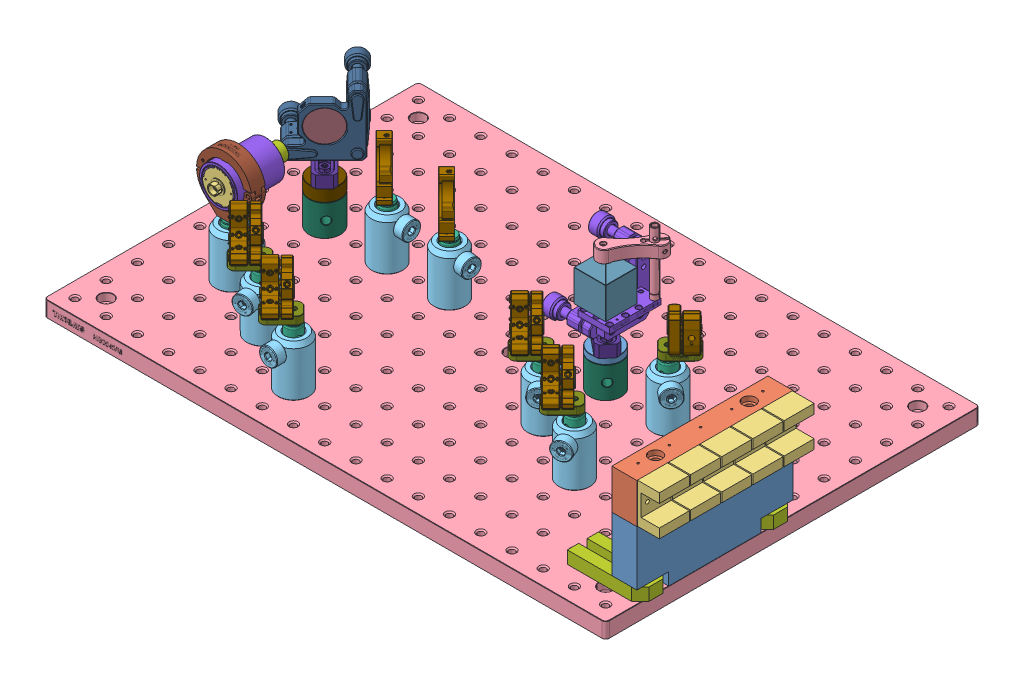
SolidWorks assembly Assem1, configuration Default. Lengths in mm.
Overall size (467.5 122.07 300).
67 component instances, 27 part files, 158 mates.
Components (placement in the parent):
- CC054-A - Base Mount-1: CC054-A - Base Mount [Default] at (68.9437 -53.2696 310.4338) x (0 0 1) z (-1 0 0) size (125 54 20)
- CC055-A - Diode Mount-1: CC055-A - Diode Mount [Default] at (58.9437 0.7304 247.9338) x (0 0 1) z (-1 0 0) size (125 32 20)
- CC056-A - Heatsink-1: CC056-A - Heatsink [Default] at (78.9437 16.7304 348.4338) x (0 -1 0) z (0 0 1) size (32 17.5 24)
- MB3045_M - 450x300M6-1: MB3045_M - 450x300M6 [Default] at (-146.0563 -65.9696 247.9338) size (450 12.7 300)
- PH40_M-P5 - Post Holder L40-1: PH40_M-P5 - Post Holder L40 [Default] at (-209.9469 -38.8243 365.1983) size (25 40.44 33)
- TR30_M-P5 - Optical Post L30-1: TR30_M-P5 - Optical Post L30 [Default] at (-33.5563 -34.349 310.4338) size (12.67 35.01 12.87)
- BA1S_M - Mounting Base-1: BA1S_M - Mounting Base [Default] at (51.1637 -48.2696 360.4338) size (58.42 10 24.99)
- KM100PM_M - Prism Mount L10-1: KM100PM_M - Prism Mount L10 [Default] at (-90.0598 -13.7458 200.6358) x (0 0 1) z (-1 0 0) size (52.45 52.45 53.15)
- KS05_M - Mirror Mount-1: KS05_M - Mirror Mount [Default] at (-35.115 17.2288 313.6155) x (-0.707107 0 -0.707107) z (0.707107 0 -0.707107) size (29.46 29.46 19.28)
- KS1 - Mirror Mount-1: KS1 - Mirror Mount [Default] at (-282.5729 -12.2533 247.4622) x (-0.707107 0 0.707107) z (-0.707107 0 -0.707107) size (52.45 52.45 42.47)
- PFM1_M - Flexure Mirror Mount-1: PFM1_M - Flexure Mirror Mount [Default] at (-127.9456 -10.3101 259.5463) x (-0.707107 0 0.707107) z (-0.707107 0 -0.707107) size (32.51 43.24 9.26) (hidden)
- SM1TC - Lens Tube Clamp-1: SM1TC - Lens Tube Clamp [Default] at (-308.5563 16.7304 310.4338) size (44.18 47.5 11.18)
- PF05-03-P01 - 05 Round Mirror-1: PF05-03-P01 - 05 Round Mirror [Default] at (-70.3657 -9.2592 301.8068) x (-0.608573 -0.509193 -0.608573) z (0.707107 0 -0.707107) size (12.7 12.7 6)
- PF10-03-P01 - 1 Round Mirror-1: PF10-03-P01 - 1 Round Mirror [Default] at (-300.01 11.2015 212.3567) x (0.707107 0 -0.707107) z (0.707107 0 0.707107) size (25.4 25.4 6)
- PBS251 - Polarizing Beamsplitter 420-680nm-1: PBS251 - Polarizing Beamsplitter 420-680nm [Default] at (-96.2563 5.3042 248.1338) size (25.4 25.4 25.4)
- RS25_M - Pillar Post L25-1: RS25_M - Pillar Post L25 [Default] at (-84.0904 -40.405 236.7511) x (0.655342 0 -0.755332) z (0.755332 0 0.655342) size (25 25 25.2)
- KCP05_M - Centering Plate-1: KCP05_M - Centering Plate [Default] at (-38.2619 1.9984 315.1394) x (0.707107 0 0.707107) z (0.707107 0 -0.707107) size (15.24 6.35 25.91)
- KMCP_M - Centering Plate-1: KMCP_M - Centering Plate [Default] at (-86.7824 -23.2708 232.8685) x (-0.632954 0 0.774189) z (0 1 0) size (15.24 34.29 9.53)
- RS10M - Post Spacer L10-1: RS10M - Post Spacer L10 [Default] at (-289.9454 -48.883 240.502) x (0.985186 0 -0.171489) z (0.171489 0 0.985186) size (25 10 25)
- RS5M - Post Spacer L05-1: RS5M - Post Spacer L05 [Default] at (-73.3037 -40.769 235.7337) x (0.8482 0 -0.529676) z (0.529676 0 0.8482) size (25 5 25)
- SM1A6 - SM1-SM05 Adapter-1: SM1A6 - SM1-SM05 Adapter [Default] at (-315.2083 22.6955 280.2399) x (0.870077 0.492915 0) z (0 0 1) size (26.29 26.29 3.81)
- SM1FC - Fiber Adapter-1: SM1FC - Fiber Adapter [Default] at (-308.5563 16.7304 321.2575) size (26.29 26.29 8.28)
- PM4_M - Clamp Arm M4-1: PM4_M - Clamp Arm M4 [Default] at (-67.8475 30.7042 211.9388) x (-0.60661 0 0.795) z (-0.795 0 -0.60661) size (43.81 55.88 12.78)
- A240TM-A - Rochester Aspheric Lens 350-700-1: A240TM-A - Rochester Aspheric Lens 350-700 [Default] at (66.5857 16.7304 360.4338) x (1 0 0) z (0 -0.655592 0.755115) size (6.86 12.24 12.24)
- AC127-019-A - Achromatic Doublet 350-700-1: AC127-019-A - Achromatic Doublet 350-700 [Default] at (-308.5563 16.7304 291.4495) x (-0.891118 -0.453772 0) z (0 0 -1) size (12.7 12.7 6)
- SM05V10 - Adjustable Lens Tube-1: SM05V10 - Adjustable Lens Tube [Default] at (-308.5563 16.7304 309.5608) x (0 0 1) z (0.988244 -0.152886 0) size (38.86 19.05 19.05)
- SM1M15 - Lens Tube-1: SM1M15 - Lens Tube [Default] at (-286.1396 25.3238 266.9462) x (-0.304458 0.952526 0) z (0 0 1) size (30.48 30.48 38.1)
- BA1S_M - Mounting Base-2: BA1S_M - Mounting Base [Default] at (51.1637 -48.2696 260.4338) size (58.42 10 24.99)
- CC056-A - Heatsink-2: CC056-A - Heatsink [Default] at (78.9437 16.7304 323.4338) x (0 -1 0) z (0 0 1) size (32 17.5 24)
- CC056-A - Heatsink-3: CC056-A - Heatsink [Default] at (78.9437 16.7304 298.4338) x (0 -1 0) z (0 0 1) size (32 17.5 24)
- CC056-A - Heatsink-4: CC056-A - Heatsink [Default] at (78.9437 16.7304 273.4338) x (0 -1 0) z (0 0 1) size (32 17.5 24)
- CC056-A - Heatsink-5: CC056-A - Heatsink [Default] at (78.9437 16.7304 248.4338) x (0 -1 0) z (0 0 1) size (32 17.5 24)
- PH40_M-P5 - Post Holder L40-2: PH40_M-P5 - Post Holder L40 [Default] at (-259.0241 -38.8243 340.375) x (0.982082 0 -0.188455) z (0.188455 0 0.982082) size (25 40.44 33)
- PH40_M-P5 - Post Holder L40-3: PH40_M-P5 - Post Holder L40 [Default] at (-32.9479 -38.8243 315.3596) x (0.918365 0 -0.395734) z (0.395734 0 0.918365) size (25 40.44 33)
- PH40_M-P5 - Post Holder L40-4: PH40_M-P5 - Post Holder L40 [Default] at (-81.8101 -38.8243 290.0798) x (0.8 0 -0.6) z (0.6 0 0.8) size (25 40.44 33)
- PH40_M-P5 - Post Holder L40-5: PH40_M-P5 - Post Holder L40 [Default] at (-30.7512 -38.8243 239.5284) x (0.63358 0 -0.773678) z (0.773678 0 0.63358) size (25 40.44 33)
- PH40_M-P5 - Post Holder L40-7: PH40_M-P5 - Post Holder L40 [Default] at (-154.3259 -38.8243 238.0295) x (0.263225 0 -0.964735) z (0.964735 0 0.263225) size (25 40.44 33) (hidden)
- PH40_M-P5 - Post Holder L40-8: PH40_M-P5 - Post Holder L40 [Default] at (-203.9934 -38.8243 237.3869) x (0.120178 0 -0.992752) z (0.992752 0 0.120178) size (25 40.44 33)
- PH40_M-P5 - Post Holder L40-9: PH40_M-P5 - Post Holder L40 [Default] at (-253.8362 -38.8243 236.9685) x (0.030377 0 -0.999538) z (0.999538 0 0.030377) size (25 40.44 33)
- PH40_M-P5 - Post Holder L40-10: PH40_M-P5 - Post Holder L40 [Default] at (-303.7918 -38.8243 311.8244) x (0 0 -1) z (1 0 0) size (25 40.44 33)
- TR30_M-P5 - Optical Post L30-2: TR30_M-P5 - Optical Post L30 [Default] at (-33.5563 -34.349 235.4338) x (0.982082 0 -0.188455) z (0.188455 0 0.982082) size (12.67 35.01 12.87)
- TR30_M-P5 - Optical Post L30-6: TR30_M-P5 - Optical Post L30 [Default] at (-83.5563 -34.349 285.4338) x (0.8 0 -0.6) z (0.6 0 0.8) size (12.67 35.01 12.87)
- TR30_M-P5 - Optical Post L30-8: TR30_M-P5 - Optical Post L30 [Default] at (-158.5563 -38.667 235.4338) x (0.63358 0 -0.773678) z (0.773678 0 0.63358) size (12.67 35.01 12.87) (hidden)
- TR30_M-P5 - Optical Post L30-10: TR30_M-P5 - Optical Post L30 [Default] at (-208.5563 -38.667 235.4338) x (0.443629 0 -0.896211) z (0.896211 0 0.443629) size (12.67 35.01 12.87)
- TR30_M-P5 - Optical Post L30-12: TR30_M-P5 - Optical Post L30 [Default] at (-208.5563 -34.349 360.4338) x (0.263225 0 -0.964735) z (0.964735 0 0.263225) size (12.67 35.01 12.87)
- TR30_M-P5 - Optical Post L30-14: TR30_M-P5 - Optical Post L30 [Default] at (-258.5563 -34.349 335.4338) x (0.120178 0 -0.992752) z (0.992752 0 0.120178) size (12.67 35.01 12.87)
- TR30_M-P5 - Optical Post L30-17: TR30_M-P5 - Optical Post L30 [Default] at (-258.5563 -38.667 235.4338) x (0.030377 0 -0.999538) z (0.999538 0 0.030377) size (12.67 35.01 12.87)
- TR30_M-P5 - Optical Post L30-19: TR30_M-P5 - Optical Post L30 [Default] at (-308.5563 -38.667 310.4338) x (0 0 -1) z (1 0 0) size (12.67 35.01 12.87)
- A240TM-A - Rochester Aspheric Lens 350-700-6: A240TM-A - Rochester Aspheric Lens 350-700 [Default] at (66.5857 16.7304 335.4338) x (1 0 0) z (0 -0.767025 0.641617) size (6.86 12.24 12.24)
- A240TM-A - Rochester Aspheric Lens 350-700-7: A240TM-A - Rochester Aspheric Lens 350-700 [Default] at (66.5857 16.7304 310.4338) x (1 0 0) z (0 -0.84248 0.538728) size (6.86 12.24 12.24)
- A240TM-A - Rochester Aspheric Lens 350-700-8: A240TM-A - Rochester Aspheric Lens 350-700 [Default] at (66.5857 16.7304 285.4338) x (1 0 0) z (0 -0.889028 0.457853) size (6.86 12.24 12.24)
- KCP05_M - Centering Plate-4: KCP05_M - Centering Plate [Default] at (-88.2619 1.9984 290.1394) x (0.707107 0 0.707107) z (0.707107 0 -0.707107) size (15.24 6.35 25.91)
- PF05-03-P01 - 05 Round Mirror-4: PF05-03-P01 - 05 Round Mirror [Default] at (-121.1332 -7.8569 276.0393) x (-0.62346 -0.471799 -0.62346) z (0.707107 0 -0.707107) size (12.7 12.7 6)
- KS05_M - Mirror Mount-4: KS05_M - Mirror Mount [Default] at (-85.115 17.2288 288.6155) x (-0.707107 0 -0.707107) z (0.707107 0 -0.707107) size (29.46 29.46 19.28)
- KCP05_M - Centering Plate-6: KCP05_M - Centering Plate [Default] at (-213.2619 1.9984 365.1394) x (0.707107 0 0.707107) z (0.707107 0 -0.707107) size (15.24 6.35 25.91)
- PF05-03-P01 - 05 Round Mirror-6: PF05-03-P01 - 05 Round Mirror [Default] at (-245.967 -8.1713 351.2055) x (-0.620263 -0.480155 -0.620263) z (0.707107 0 -0.707107) size (12.7 12.7 6)
- KS05_M - Mirror Mount-6: KS05_M - Mirror Mount [Default] at (-210.115 17.2288 363.6155) x (-0.707107 0 -0.707107) z (0.707107 0 -0.707107) size (29.46 29.46 19.28)
- KCP05_M - Centering Plate-8: KCP05_M - Centering Plate [Default] at (-263.2619 1.9984 340.1394) x (0.707107 0 0.707107) z (0.707107 0 -0.707107) size (15.24 6.35 25.91)
- PF05-03-P01 - 05 Round Mirror-8: PF05-03-P01 - 05 Round Mirror [Default] at (-295.0328 -9.8306 327.1397) x (-0.602026 -0.524528 -0.602026) z (0.707107 0 -0.707107) size (12.7 12.7 6)
- KS05_M - Mirror Mount-8: KS05_M - Mirror Mount [Default] at (-260.115 17.2288 338.6155) x (-0.707107 0 -0.707107) z (0.707107 0 -0.707107) size (29.46 29.46 19.28)
- KCP05_M - Centering Plate-10: KCP05_M - Centering Plate [Default] at (-28.8506 1.9984 230.7281) x (-0.707107 0 -0.707107) z (-0.707107 0 0.707107) size (15.24 6.35 25.91)
- PF05-03-P01 - 05 Round Mirror-10: PF05-03-P01 - 05 Round Mirror [Default] at (1.5654 -11.9598 242.373) x (0.574886 -0.582247 0.574886) z (-0.707107 0 0.707107) size (12.7 12.7 6)
- KS05_M - Mirror Mount-10: KS05_M - Mirror Mount [Default] at (-31.9976 17.2288 232.252) x (0.707107 0 0.707107) z (-0.707107 0 0.707107) size (29.46 29.46 19.28)
- PFM1_M - Flexure Mirror Mount-2: PFM1_M - Flexure Mirror Mount [Default] at (-232.6688 -10.3101 266.0445) x (-0.707107 0 -0.707107) z (0.707107 0 -0.707107) size (32.51 43.24 9.26)
- PFM1_M - Flexure Mirror Mount-4: PFM1_M - Flexure Mirror Mount [Default] at (-282.6688 -10.3101 266.0445) x (-0.707107 0 -0.707107) z (0.707107 0 -0.707107) size (32.51 43.24 9.26)
- RS25_M - Pillar Post L25-2: RS25_M - Pillar Post L25 [Default] at (-309.0904 -40.405 236.7511) x (0.655342 0 -0.755332) z (0.755332 0 0.655342) size (25 25 25.2)
- KMCP_M - Centering Plate-2: KMCP_M - Centering Plate [Default] at (-311.5101 -18.2696 232.5591) x (-0.707107 0 0.707107) z (0 1 0) size (15.24 34.29 9.53)
Mates (geometry in assembly coordinates):
- Concentric1: concentric: cylinder of CC054-A - Base Mount-1 through (68.9437 -43.2696 360.4338) axis (0 -1 0) radius 2.5; cylinder of BA1S_M - Mounting Base-1 through (68.9437 -53.2696 360.4338) axis (0 1 0) radius 3.3655
- Coincident1: coincident: plane of CC054-A - Base Mount-1 through (58.9437 -43.2696 347.4338) normal (0 -1 0); plane of BA1S_M - Mounting Base-1 through (2.8683 -43.2696 360.4338) normal (0 1 0)
- Parallel1: parallel: plane of CC054-A - Base Mount-1 through (58.9437 -43.2696 372.9338) normal (0 0 1); plane of BA1S_M - Mounting Base-1 through (2.8683 -53.2696 372.9306) normal (0 0 1)
- Concentric2: concentric: cylinder of CC054-A - Base Mount-1 through (68.9437 -43.2696 260.4338) axis (0 -1 0) radius 2.5; cylinder of BA1S_M - Mounting Base-2 through (68.9437 -53.2696 260.4338) axis (0 1 0) radius 3.3655
- Coincident2: coincident: plane of CC054-A - Base Mount-1 through (58.9437 -43.2696 247.9338) normal (0 -1 0); plane of BA1S_M - Mounting Base-2 through (2.8683 -43.2696 260.4338) normal (0 1 0)
- Parallel2: parallel: plane of CC054-A - Base Mount-1 through (58.9437 0.7304 247.9338) normal (0 0 -1); plane of BA1S_M - Mounting Base-2 through (2.8683 -53.2696 247.937) normal (0 0 -1)
- Coincident3: coincident: plane of MB3045_M - 450x300M6-1 through (-368.0563 -53.2696 394.9338) normal (0 1 0); plane of BA1S_M - Mounting Base-1 through (2.8683 -53.2696 360.4338) normal (0 -1 0)
- Coincident4: coincident: plane of CC054-A - Base Mount-1 through (78.9437 -53.2696 310.4338) normal (1 0 0); plane of MB3045_M - 450x300M6-1 through (78.9437 -53.2696 394.9338) normal (1 0 0)
- Concentric3: concentric: cylinder of CC054-A - Base Mount-1 through (68.9437 0.7304 347.9338) axis (0 1 0) radius 2.5; cylinder of CC055-A - Diode Mount-1 through (68.9437 32.7304 347.9338) axis (0 1 0) radius 5.25
- Concentric4: concentric: cylinder of CC054-A - Base Mount-1 through (68.9437 0.7304 272.9338) axis (0 1 0) radius 2.5; cylinder of CC055-A - Diode Mount-1 through (68.9437 32.7304 272.9338) axis (0 1 0) radius 5.25
- Coincident5: coincident: plane of CC054-A - Base Mount-1 through (58.9437 0.7304 372.9338) normal (0 1 0); plane of CC055-A - Diode Mount-1 through (58.9437 0.7304 247.9338) normal (0 -1 0)
- Concentric5: concentric: cylinder of CC055-A - Diode Mount-1 through (78.9437 16.7304 367.4338) axis (1 0 0) radius 1.25; cylinder of CC056-A - Heatsink-1 through (78.9427 16.7304 367.4338) axis (1 0 0) radius 1.5
- Concentric6: concentric: cylinder of CC055-A - Diode Mount-1 through (78.9437 16.7304 353.4338) axis (1 0 0) radius 1.25; cylinder of CC056-A - Heatsink-1 through (78.9427 16.7304 353.4338) axis (1 0 0) radius 1.5
- Coincident6: coincident: plane of CC055-A - Diode Mount-1 through (78.9437 32.7304 247.9338) normal (1 0 0); plane of CC056-A - Heatsink-1 through (78.9437 32.7304 372.4338) normal (-1 0 0)
- Coincident7: coincident: plane of CC055-A - Diode Mount-1 through (78.9437 32.7304 247.9338) normal (1 0 0); plane of CC056-A - Heatsink-2 through (78.9437 32.7304 347.4338) normal (-1 0 0)
- Concentric7: concentric: cylinder of CC055-A - Diode Mount-1 through (78.9437 16.7304 342.4338) axis (1 0 0) radius 1.25; cylinder of CC056-A - Heatsink-2 through (78.9427 16.7304 342.4338) axis (1 0 0) radius 1.5
- Concentric8: concentric: cylinder of CC055-A - Diode Mount-1 through (78.9437 16.7304 328.4338) axis (1 0 0) radius 1.25; cylinder of CC056-A - Heatsink-2 through (78.9427 16.7304 328.4338) axis (1 0 0) radius 1.5
- Coincident8: coincident: plane of CC055-A - Diode Mount-1 through (78.9437 32.7304 247.9338) normal (1 0 0); plane of CC056-A - Heatsink-3 through (78.9437 32.7304 322.4338) normal (-1 0 0)
- Concentric9: concentric: cylinder of CC055-A - Diode Mount-1 through (78.9437 16.7304 317.4338) axis (1 0 0) radius 1.25; cylinder of CC056-A - Heatsink-3 through (78.9427 16.7304 317.4338) axis (1 0 0) radius 1.5
- Concentric10: concentric: cylinder of CC055-A - Diode Mount-1 through (78.9437 16.7304 303.4338) axis (1 0 0) radius 1.25; cylinder of CC056-A - Heatsink-3 through (78.9427 16.7304 303.4338) axis (1 0 0) radius 1.5
- Coincident9: coincident: plane of CC055-A - Diode Mount-1 through (78.9437 32.7304 247.9338) normal (1 0 0); plane of CC056-A - Heatsink-4 through (78.9437 32.7304 297.4338) normal (-1 0 0)
- Concentric11: concentric: cylinder of CC055-A - Diode Mount-1 through (78.9437 16.7304 292.4338) axis (1 0 0) radius 1.25; cylinder of CC056-A - Heatsink-4 through (78.9427 16.7304 292.4338) axis (1 0 0) radius 1.5
- Concentric12: concentric: cylinder of CC055-A - Diode Mount-1 through (78.9437 16.7304 278.4338) axis (1 0 0) radius 1.25; cylinder of CC056-A - Heatsink-4 through (78.9427 16.7304 278.4338) axis (1 0 0) radius 1.5
- Coincident10: coincident: plane of CC055-A - Diode Mount-1 through (78.9437 32.7304 247.9338) normal (1 0 0); plane of CC056-A - Heatsink-5 through (78.9437 32.7304 272.4338) normal (-1 0 0)
- Concentric13: concentric: cylinder of CC055-A - Diode Mount-1 through (78.9437 16.7304 267.4338) axis (1 0 0) radius 1.25; cylinder of CC056-A - Heatsink-5 through (78.9427 16.7304 267.4338) axis (1 0 0) radius 1.5
- Concentric14: concentric: cylinder of CC055-A - Diode Mount-1 through (78.9437 16.7304 253.4338) axis (1 0 0) radius 1.25; cylinder of CC056-A - Heatsink-5 through (78.9427 16.7304 253.4338) axis (1 0 0) radius 1.5
- Width2: width: plane of BA1S_M - Mounting Base-1 through (2.8683 -53.2696 357.0683) normal (0 0 1); plane of BA1S_M - Mounting Base-1 through (2.8683 -53.2696 363.7993) normal (0 0 -1); cylinder of MB3045_M - 450x300M6-1 through (41.4437 -53.2696 360.4338) axis (0 1 0) radius 2.5
- Coincident12: coincident: plane of MB3045_M - 450x300M6-1 through (-368.0563 -53.2696 394.9338) normal (0 1 0); plane of PH40_M-P5 - Post Holder L40-1 through (-236.1977 -53.2696 360.4338) normal (0 -1 0)
- Concentric15: concentric: cylinder of MB3045_M - 450x300M6-1 through (-208.5563 -53.2696 360.4338) axis (0 1 0) radius 2.5; cylinder of PH40_M-P5 - Post Holder L40-1 through (-208.5563 -52.3806 360.4338) axis (0 -1 0) radius 2.5
- Coincident13: coincident: plane of MB3045_M - 450x300M6-1 through (-368.0563 -53.2696 394.9338) normal (0 1 0); plane of PH40_M-P5 - Post Holder L40-2 through (-285.7024 -53.2696 340.6429) normal (0 -1 0)
- Concentric16: concentric: cylinder of MB3045_M - 450x300M6-1 through (-258.5563 -53.2696 335.4338) axis (0 1 0) radius 2.5; cylinder of PH40_M-P5 - Post Holder L40-2 through (-258.5563 -52.3806 335.4338) axis (0 -1 0) radius 2.5
- Coincident14: coincident: plane of MB3045_M - 450x300M6-1 through (-368.0563 -53.2696 394.9338) normal (0 1 0); plane of PH40_M-P5 - Post Holder L40-3 through (-58.9412 -53.2696 321.3724) normal (0 -1 0)
- Concentric17: concentric: cylinder of MB3045_M - 450x300M6-1 through (-33.5563 -53.2696 310.4338) axis (0 1 0) radius 2.5; cylinder of PH40_M-P5 - Post Holder L40-3 through (-33.5563 -52.3806 310.4338) axis (0 -1 0) radius 2.5
- Coincident15: coincident: plane of MB3045_M - 450x300M6-1 through (-368.0563 -53.2696 394.9338) normal (0 1 0); plane of PH40_M-P5 - Post Holder L40-4 through (-105.6694 -53.2696 302.0186) normal (0 -1 0)
- Concentric18: concentric: cylinder of MB3045_M - 450x300M6-1 through (-83.5563 -53.2696 285.4338) axis (0 1 0) radius 2.5; cylinder of PH40_M-P5 - Post Holder L40-4 through (-83.5563 -52.3806 285.4338) axis (0 -1 0) radius 2.5
- Coincident16: coincident: plane of MB3045_M - 450x300M6-1 through (-368.0563 -53.2696 394.9338) normal (0 1 0); plane of PH40_M-P5 - Post Holder L40-5 through (-51.0693 -53.2696 256.8193) normal (0 -1 0)
- Concentric19: concentric: cylinder of MB3045_M - 450x300M6-1 through (-33.5563 -53.2696 235.4338) axis (0 1 0) radius 2.5; cylinder of PH40_M-P5 - Post Holder L40-5 through (-33.5563 -52.3806 235.4338) axis (0 -1 0) radius 2.5
- Coincident18: coincident: plane of MB3045_M - 450x300M6-1 through (-368.0563 -53.2696 394.9338) normal (0 1 0); plane of PH40_M-P5 - Post Holder L40-7 through (-165.8322 -53.2696 262.1004) normal (0 -1 0)
- Concentric21: concentric: cylinder of MB3045_M - 450x300M6-1 through (-158.5563 -53.2696 235.4338) axis (0 1 0) radius 2.5; cylinder of PH40_M-P5 - Post Holder L40-7 through (-158.5563 -52.3806 235.4338) axis (0 -1 0) radius 2.5
- Coincident19: coincident: plane of MB3045_M - 450x300M6-1 through (-368.0563 -53.2696 394.9338) normal (0 1 0); plane of PH40_M-P5 - Post Holder L40-8 through (-211.8782 -53.2696 262.8748) normal (0 -1 0)
- Concentric22: concentric: cylinder of MB3045_M - 450x300M6-1 through (-208.5563 -53.2696 235.4338) axis (0 1 0) radius 2.5; cylinder of PH40_M-P5 - Post Holder L40-8 through (-208.5563 -52.3806 235.4338) axis (0 -1 0) radius 2.5
- Coincident20: coincident: plane of MB3045_M - 450x300M6-1 through (-368.0563 -53.2696 394.9338) normal (0 1 0); plane of PH40_M-P5 - Post Holder L40-9 through (-259.3959 -53.2696 263.0624) normal (0 -1 0)
- Concentric23: concentric: cylinder of MB3045_M - 450x300M6-1 through (-258.5563 -53.2696 235.4338) axis (0 1 0) radius 2.5; cylinder of PH40_M-P5 - Post Holder L40-9 through (-258.5563 -52.3806 235.4338) axis (0 -1 0) radius 2.5
- Coincident21: coincident: plane of MB3045_M - 450x300M6-1 through (-368.0563 -53.2696 394.9338) normal (0 1 0); plane of PH40_M-P5 - Post Holder L40-10 through (-308.5563 -53.2696 338.0752) normal (0 -1 0)
- Concentric24: concentric: cylinder of MB3045_M - 450x300M6-1 through (-308.5563 -53.2696 310.4338) axis (0 1 0) radius 2.5; cylinder of PH40_M-P5 - Post Holder L40-10 through (-308.5563 -52.3806 310.4338) axis (0 -1 0) radius 2.5
- Concentric25: concentric: cylinder of TR30_M-P5 - Optical Post L30-1 through (-33.5563 -4.3516 310.4338) axis (0 1 0) radius 6.3373; cylinder of PH40_M-P5 - Post Holder L40-3 through (-33.5563 -13.2696 310.4338) axis (0 -1 0) radius 6.3881
- Concentric26: concentric: cylinder of PH40_M-P5 - Post Holder L40-5 through (-33.5563 -13.2696 235.4338) axis (0 -1 0) radius 6.3881; cylinder of TR30_M-P5 - Optical Post L30-2 through (-33.5563 -4.3516 235.4338) axis (0 1 0) radius 6.3373
- Concentric28: concentric: cylinder of PH40_M-P5 - Post Holder L40-4 through (-83.5563 -13.2696 285.4338) axis (0 -1 0) radius 6.3881; cylinder of TR30_M-P5 - Optical Post L30-6 through (-83.5563 -4.3516 285.4338) axis (0 1 0) radius 6.3373
- Concentric29: concentric: cylinder of PH40_M-P5 - Post Holder L40-7 through (-158.5563 -13.2696 235.4338) axis (0 -1 0) radius 6.3881; cylinder of TR30_M-P5 - Optical Post L30-8 through (-158.5563 12.4946 235.4338) axis (0 1 0) radius 6.3373
- Concentric30: concentric: cylinder of PH40_M-P5 - Post Holder L40-8 through (-208.5563 -13.2696 235.4338) axis (0 -1 0) radius 6.3881; cylinder of TR30_M-P5 - Optical Post L30-10 through (-208.5563 12.4946 235.4338) axis (0 1 0) radius 6.3373
- Concentric31: concentric: cylinder of PH40_M-P5 - Post Holder L40-1 through (-208.5563 -13.2696 360.4338) axis (0 -1 0) radius 6.3881; cylinder of TR30_M-P5 - Optical Post L30-12 through (-208.5563 -4.3516 360.4338) axis (0 1 0) radius 6.3373
- Concentric32: concentric: cylinder of PH40_M-P5 - Post Holder L40-2 through (-258.5563 -13.2696 335.4338) axis (0 -1 0) radius 6.3881; cylinder of TR30_M-P5 - Optical Post L30-14 through (-258.5563 -4.3516 335.4338) axis (0 1 0) radius 6.3373
- Concentric33: concentric: cylinder of PH40_M-P5 - Post Holder L40-9 through (-258.5563 -13.2696 235.4338) axis (0 -1 0) radius 6.3881; cylinder of TR30_M-P5 - Optical Post L30-17 through (-258.5563 12.4946 235.4338) axis (0 1 0) radius 6.3373
- Concentric34: concentric: cylinder of PH40_M-P5 - Post Holder L40-10 through (-308.5563 -13.2696 310.4338) axis (0 -1 0) radius 6.3881; cylinder of TR30_M-P5 - Optical Post L30-19 through (-308.5563 -8.6696 310.4338) axis (0 1 0) radius 6.3373
- Concentric35: concentric: cylinder of SM1TC - Lens Tube Clamp-1 through (-308.5563 19.7784 310.4338) axis (0 -1 0) radius 2.3876; cylinder of TR30_M-P5 - Optical Post L30-19 through (-308.5563 -15.7166 310.4338) axis (0 -1 0) radius 2
- Coincident23: coincident: plane of SM1TC - Lens Tube Clamp-1 through (-314.2713 -8.6696 316.0218) normal (0 -1 0); plane of TR30_M-P5 - Optical Post L30-19 through (-308.5563 -8.6696 310.4338) normal (0 1 0)
- Concentric36: concentric: cylinder of SM1TC - Lens Tube Clamp-1 through (-308.5563 16.7304 316.0218) axis (0 0 -1) radius 15.367; cylinder of SM1M15 - Lens Tube-1 through (-308.5563 16.7304 320.686) axis (0 0 1) radius 15.24
- Concentric37: concentric: cylinder of CC055-A - Diode Mount-1 through (62.9437 16.7304 360.4338) axis (-1 0 0) radius 6.4897; cylinder of A240TM-A - Rochester Aspheric Lens 350-700-1 through (66.5857 16.7304 360.4338) axis (-1 0 0) radius 6.1201
- Coincident24: coincident: circle of CC055-A - Diode Mount-1; plane of A240TM-A - Rochester Aspheric Lens 350-700-1 through (73.4437 21.2611 364.3673) normal (1 0 0)
- Coincident25: coincident: circle of CC055-A - Diode Mount-1; plane of A240TM-A - Rochester Aspheric Lens 350-700-6 through (73.4437 20.5801 340.0359) normal (1 0 0)
- Concentric40: concentric: cylinder of CC055-A - Diode Mount-1 through (69.4437 16.7304 335.4338) axis (-1 0 0) radius 6.5; cylinder of A240TM-A - Rochester Aspheric Lens 350-700-6 through (66.5857 16.7304 335.4338) axis (-1 0 0) radius 6.1201
- Coincident26: coincident: circle of CC055-A - Diode Mount-1; plane of A240TM-A - Rochester Aspheric Lens 350-700-7 through (73.4437 19.9628 315.4886) normal (1 0 0)
- Concentric41: concentric: cylinder of CC055-A - Diode Mount-1 through (69.4437 16.7304 310.4338) axis (-1 0 0) radius 6.5; cylinder of A240TM-A - Rochester Aspheric Lens 350-700-7 through (66.5857 16.7304 310.4338) axis (-1 0 0) radius 6.1201
- Coincident27: coincident: circle of CC055-A - Diode Mount-1; plane of A240TM-A - Rochester Aspheric Lens 350-700-8 through (73.4437 19.4775 290.7679) normal (1 0 0)
- Concentric42: concentric: cylinder of CC055-A - Diode Mount-1 through (69.4437 16.7304 285.4338) axis (-1 0 0) radius 6.5; cylinder of A240TM-A - Rochester Aspheric Lens 350-700-8 through (66.5857 16.7304 285.4338) axis (-1 0 0) radius 6.1201
- Concentric43: concentric: cylinder of TR30_M-P5 - Optical Post L30-1 through (-33.5563 -11.3986 310.4338) axis (0 -1 0) radius 2; cylinder of KCP05_M - Centering Plate-1 through (-33.5563 1.9984 310.4338) axis (0 1 0) radius 2
- Coincident29: coincident: plane of TR30_M-P5 - Optical Post L30-1 through (-33.5563 -4.3516 310.4338) normal (0 1 0); plane of KCP05_M - Centering Plate-1 through (-34.6698 -4.3516 300.771) normal (0 -1 0)
- Concentric44: concentric: cylinder of KS05_M - Mirror Mount-1 through (-42.9676 1.9984 319.8451) axis (0 -1 0) radius 2; cylinder of KCP05_M - Centering Plate-1 through (-42.9676 -4.3516 319.8451) axis (0 -1 0) radius 2.3813
- Coincident30: coincident: plane of KS05_M - Mirror Mount-1 through (-50.4212 1.9984 319.7553) normal (0 -1 0); plane of KCP05_M - Centering Plate-1 through (-34.6698 1.9984 300.771) normal (0 1 0)
- Concentric45: concentric: cylinder of KS05_M - Mirror Mount-1 through (-38.6571 16.7304 315.5345) axis (0.707107 0 -0.707107) radius 5.969; cylinder of PF05-03-P01 - 05 Round Mirror-1 through (-33.1572 16.7304 310.0347) axis (-0.707107 0 0.707107) radius 6.35
- Coincident31: coincident: plane of KS05_M - Mirror Mount-1 through (-47.2781 2.7604 304.399) normal (0.707107 0 -0.707107); plane of PF05-03-P01 - 05 Round Mirror-1 through (-37.3998 16.7304 314.2773) normal (-0.707107 0 0.707107)
- Parallel3: parallel: plane of KS05_M - Mirror Mount-1 through (-36.2324 5.6154 333.9441) normal (0.707107 0 0.707107); plane of KCP05_M - Centering Plate-1 through (-42.2132 -4.3516 329.867) normal (0.707107 0 0.707107)
- Concentric51: concentric: cylinder of KCP05_M - Centering Plate-4 through (-92.9676 -4.3516 294.8451) axis (0 -1 0) radius 2.3813; cylinder of KS05_M - Mirror Mount-4 through (-92.9676 1.9984 294.8451) axis (0 -1 0) radius 2
- Coincident37: coincident: plane of KCP05_M - Centering Plate-4 through (-84.6698 1.9984 275.771) normal (0 1 0); plane of KS05_M - Mirror Mount-4 through (-100.4212 1.9984 294.7553) normal (0 -1 0)
- Concentric52: concentric: cylinder of PF05-03-P01 - 05 Round Mirror-4 through (-83.1572 16.7304 285.0347) axis (-0.707107 0 0.707107) radius 6.35; cylinder of KS05_M - Mirror Mount-4 through (-88.6571 16.7304 290.5345) axis (0.707107 0 -0.707107) radius 5.969
- Coincident38: coincident: plane of PF05-03-P01 - 05 Round Mirror-4 through (-87.3998 16.7304 289.2773) normal (-0.707107 0 0.707107); plane of KS05_M - Mirror Mount-4 through (-97.2781 2.7604 279.399) normal (0.707107 0 -0.707107)
- Parallel6: parallel: plane of KCP05_M - Centering Plate-4 through (-92.2132 -4.3516 304.867) normal (0.707107 0 0.707107); plane of KS05_M - Mirror Mount-4 through (-86.2324 5.6154 308.9441) normal (0.707107 0 0.707107)
- Concentric53: concentric: circle of TR30_M-P5 - Optical Post L30-6; cylinder of KCP05_M - Centering Plate-4 through (-83.5563 1.9984 285.4338) axis (0 1 0) radius 2
- Coincident39: coincident: plane of TR30_M-P5 - Optical Post L30-6 through (-83.5563 -4.3516 285.4338) normal (0 1 0); plane of KCP05_M - Centering Plate-4 through (-84.6698 -4.3516 275.771) normal (0 -1 0)
- Concentric56: concentric: cylinder of KCP05_M - Centering Plate-6 through (-217.9676 -4.3516 369.8451) axis (0 -1 0) radius 2.3813; cylinder of KS05_M - Mirror Mount-6 through (-217.9676 1.9984 369.8451) axis (0 -1 0) radius 2
- Coincident42: coincident: plane of KCP05_M - Centering Plate-6 through (-209.6698 1.9984 350.771) normal (0 1 0); plane of KS05_M - Mirror Mount-6 through (-225.4212 1.9984 369.7553) normal (0 -1 0)
- Concentric57: concentric: cylinder of PF05-03-P01 - 05 Round Mirror-6 through (-208.1572 16.7304 360.0347) axis (-0.707107 0 0.707107) radius 6.35; cylinder of KS05_M - Mirror Mount-6 through (-213.6571 16.7304 365.5345) axis (0.707107 0 -0.707107) radius 5.969
- Coincident43: coincident: plane of PF05-03-P01 - 05 Round Mirror-6 through (-212.3998 16.7304 364.2773) normal (-0.707107 0 0.707107); plane of KS05_M - Mirror Mount-6 through (-222.2781 2.7604 354.399) normal (0.707107 0 -0.707107)
- Parallel8: parallel: plane of KCP05_M - Centering Plate-6 through (-217.2132 -4.3516 379.867) normal (0.707107 0 0.707107); plane of KS05_M - Mirror Mount-6 through (-211.2324 5.6154 383.9441) normal (0.707107 0 0.707107)
- Concentric58: concentric: cylinder of TR30_M-P5 - Optical Post L30-12 through (-208.5563 -11.3986 360.4338) axis (0 -1 0) radius 2; cylinder of KCP05_M - Centering Plate-6 through (-208.5563 1.9984 360.4338) axis (0 1 0) radius 2
- Coincident44: coincident: plane of TR30_M-P5 - Optical Post L30-12 through (-208.5563 -4.3516 360.4338) normal (0 1 0); plane of KCP05_M - Centering Plate-6 through (-209.6698 -4.3516 350.771) normal (0 -1 0)
- Concentric61: concentric: cylinder of KCP05_M - Centering Plate-8 through (-267.9676 -4.3516 344.8451) axis (0 -1 0) radius 2.3813; cylinder of KS05_M - Mirror Mount-8 through (-267.9676 1.9984 344.8451) axis (0 -1 0) radius 2
- Coincident47: coincident: plane of KCP05_M - Centering Plate-8 through (-259.6698 1.9984 325.771) normal (0 1 0); plane of KS05_M - Mirror Mount-8 through (-275.4212 1.9984 344.7553) normal (0 -1 0)
- Concentric62: concentric: cylinder of PF05-03-P01 - 05 Round Mirror-8 through (-258.1572 16.7304 335.0347) axis (-0.707107 0 0.707107) radius 6.35; cylinder of KS05_M - Mirror Mount-8 through (-263.6571 16.7304 340.5345) axis (0.707107 0 -0.707107) radius 5.969
- Coincident48: coincident: plane of PF05-03-P01 - 05 Round Mirror-8 through (-262.3998 16.7304 339.2773) normal (-0.707107 0 0.707107); plane of KS05_M - Mirror Mount-8 through (-272.2781 2.7604 329.399) normal (0.707107 0 -0.707107)
- Parallel10: parallel: plane of KCP05_M - Centering Plate-8 through (-267.2132 -4.3516 354.867) normal (0.707107 0 0.707107); plane of KS05_M - Mirror Mount-8 through (-261.2324 5.6154 358.9441) normal (0.707107 0 0.707107)
- Concentric63: concentric: cylinder of TR30_M-P5 - Optical Post L30-14 through (-258.5563 -11.3986 335.4338) axis (0 -1 0) radius 2; cylinder of KCP05_M - Centering Plate-8 through (-258.5563 1.9984 335.4338) axis (0 1 0) radius 2
- Coincident49: coincident: plane of TR30_M-P5 - Optical Post L30-14 through (-258.5563 -4.3516 335.4338) normal (0 1 0); plane of KCP05_M - Centering Plate-8 through (-259.6698 -4.3516 325.771) normal (0 -1 0)
- Concentric66: concentric: cylinder of KCP05_M - Centering Plate-10 through (-24.145 -4.3516 226.0225) axis (0 -1 0) radius 2.3813; cylinder of KS05_M - Mirror Mount-10 through (-24.145 1.9984 226.0225) axis (0 -1 0) radius 2
- Coincident52: coincident: plane of KCP05_M - Centering Plate-10 through (-32.4427 1.9984 245.0965) normal (0 1 0); plane of KS05_M - Mirror Mount-10 through (-16.6914 1.9984 226.1123) normal (0 -1 0)
- Concentric67: concentric: cylinder of PF05-03-P01 - 05 Round Mirror-10 through (-33.9554 16.7304 235.8329) axis (0.707107 0 -0.707107) radius 6.35; cylinder of KS05_M - Mirror Mount-10 through (-28.4555 16.7304 230.333) axis (-0.707107 0 0.707107) radius 5.969
- Coincident53: coincident: plane of PF05-03-P01 - 05 Round Mirror-10 through (-29.7127 16.7304 231.5902) normal (0.707107 0 -0.707107); plane of KS05_M - Mirror Mount-10 through (-19.8344 2.7604 241.4685) normal (-0.707107 0 0.707107)
- Parallel12: parallel: plane of KCP05_M - Centering Plate-10 through (-24.8993 -4.3516 216.0005) normal (-0.707107 0 -0.707107); plane of KS05_M - Mirror Mount-10 through (-30.8802 5.6154 211.9235) normal (-0.707107 0 -0.707107)
- Concentric68: concentric: cylinder of TR30_M-P5 - Optical Post L30-2 through (-33.5563 -11.3986 235.4338) axis (0 -1 0) radius 2; cylinder of KCP05_M - Centering Plate-10 through (-33.5563 1.9984 235.4338) axis (0 1 0) radius 2
- Coincident54: coincident: plane of TR30_M-P5 - Optical Post L30-2 through (-33.5563 -4.3516 235.4338) normal (0 1 0); plane of KCP05_M - Centering Plate-10 through (-32.4427 -4.3516 245.0965) normal (0 -1 0)
- Coincident57: coincident: plane of KS05_M - Mirror Mount-1 through (-29.9157 25.8744 314.218) normal (0 1 0); plane of KS05_M - Mirror Mount-10 through (-37.1969 25.8744 231.6495) normal (0 1 0)
- Coincident58: coincident: plane of KS05_M - Mirror Mount-1 through (-29.9157 25.8744 314.218) normal (0 1 0); plane of KS05_M - Mirror Mount-4 through (-79.9157 25.8744 289.218) normal (0 1 0)
- Coincident59: coincident: plane of KS05_M - Mirror Mount-4 through (-79.9157 25.8744 289.218) normal (0 1 0); plane of KS05_M - Mirror Mount-6 through (-204.9157 25.8744 364.218) normal (0 1 0)
- Coincident60: coincident: plane of KS05_M - Mirror Mount-6 through (-204.9157 25.8744 364.218) normal (0 1 0); plane of KS05_M - Mirror Mount-8 through (-254.9157 25.8744 339.218) normal (0 1 0)
- Concentric71: concentric: cylinder of MB3045_M - 450x300M6-1 through (-83.5563 -53.2696 235.4338) axis (0 1 0) radius 2.5; cylinder of RS25_M - Pillar Post L25-1 through (-83.5563 -52.7616 235.4338) axis (0 -1 0) radius 3
- Coincident61: coincident: plane of MB3045_M - 450x300M6-1 through (-368.0563 -53.2696 394.9338) normal (0 1 0); plane of RS25_M - Pillar Post L25-1 through (-83.5563 -53.2696 235.4338) normal (0 -1 0)
- Concentric72: concentric: cylinder of RS25_M - Pillar Post L25-1 through (-83.5563 -28.7776 235.4338) axis (0 1 0) radius 3; cylinder of RS5M - Post Spacer L05-1 through (-83.5563 -23.2708 235.4338) axis (0 -1 0) radius 3.3655
- Coincident62: coincident: plane of RS25_M - Pillar Post L25-1 through (-83.5563 -28.2696 235.4338) normal (0 1 0); plane of RS5M - Post Spacer L05-1 through (-83.5563 -28.2696 235.4338) normal (0 -1 0)
- Concentric73: concentric: cylinder of KMCP_M - Centering Plate-1 through (-83.5563 -18.7179 235.4338) axis (0 1 0) radius 1.6532; cylinder of RS5M - Post Spacer L05-1 through (-83.5563 -23.2708 235.4338) axis (0 -1 0) radius 3.3655
- Coincident63: coincident: plane of KMCP_M - Centering Plate-1 through (-86.7824 -23.2708 232.8685) normal (0 -1 0); plane of RS5M - Post Spacer L05-1 through (-83.5563 -23.2708 235.4338) normal (0 1 0)
- Concentric74: concentric: cylinder of KM100PM_M - Prism Mount L10-1 through (-95.1398 -1.5538 226.0358) axis (0 1 0) radius 2.3813; cylinder of KMCP_M - Centering Plate-1 through (-95.1398 -13.7458 226.0358) axis (0 -1 0) radius 2.3876
- Coincident64: coincident: plane of KM100PM_M - Prism Mount L10-1 through (-100.2198 -13.7458 213.2088) normal (0 -1 0); plane of KMCP_M - Centering Plate-1 through (-86.7824 -13.7458 232.8685) normal (0 1 0)
- Parallel14: parallel: plane of CC054-A - Base Mount-1 through (58.9437 -53.2696 310.4338) normal (-1 0 0); plane of KM100PM_M - Prism Mount L10-1 through (-100.2198 32.406 203.9378) normal (-1 0 0)
- Coincident65: coincident: plane of KM100PM_M - Prism Mount L10-1 through (-65.3075 5.3042 209.3988) normal (0 1 0); plane of PBS251 - Polarizing Beamsplitter 420-680nm-1 through (-70.8563 5.3042 222.7338) normal (0 -1 0)
- Width3: width: plane of PBS251 - Polarizing Beamsplitter 420-680nm-1 through (-70.8563 30.7042 222.7338) normal (0 0 -1); plane of PBS251 - Polarizing Beamsplitter 420-680nm-1 through (-70.8563 30.7042 248.1338) normal (0 0 1); cylinder of RS25_M - Pillar Post L25-1 through (-83.5563 -28.2696 235.4338) axis (0 -1 0) radius 12.5
- Width4: width: plane of PBS251 - Polarizing Beamsplitter 420-680nm-1 through (-96.2563 30.7042 248.1338) normal (-1 0 0); plane of PBS251 - Polarizing Beamsplitter 420-680nm-1 through (-70.8563 30.7042 248.1338) normal (1 0 0); cylinder of RS25_M - Pillar Post L25-1 through (-83.5563 -28.2696 235.4338) axis (0 -1 0) radius 12.5
- Concentric75: concentric: cylinder of KM100PM_M - Prism Mount L10-1 through (-67.8475 0.7322 211.9388) axis (0 -1 0) radius 2; cylinder of PM4_M - Clamp Arm M4-1 through (-67.8475 56.1042 211.9388) axis (0 1 0) radius 2.9972
- Coincident66: coincident: plane of KM100PM_M - Prism Mount L10-1 through (-65.3075 5.3042 209.3988) normal (0 1 0); plane of PM4_M - Clamp Arm M4-1 through (-66.7623 5.3042 212.7668) normal (0 -1 0)
- Width5: width: plane of KM100PM_M - Prism Mount L10-1 through (-81.1825 5.3042 220.3208) normal (0 0 -1); plane of KM100PM_M - Prism Mount L10-1 through (-90.7075 5.3042 250.5468) normal (0 0 1); plane of PBS251 - Polarizing Beamsplitter 420-680nm-1 through (-70.8563 30.7042 248.1338) normal (0 0 1); plane of PBS251 - Polarizing Beamsplitter 420-680nm-1 through (-70.8563 30.7042 222.7338) normal (0 0 -1)
- Concentric76: concentric: cylinder of PFM1_M - Flexure Mirror Mount-1 through (-158.5563 12.4946 235.4338) axis (0 -1 0) radius 1.65; cylinder of TR30_M-P5 - Optical Post L30-8 through (-158.5563 5.4476 235.4338) axis (0 -1 0) radius 2
- Coincident67: coincident: plane of PFM1_M - Flexure Mirror Mount-1 through (-175.4392 12.4946 248.1857) normal (0 -1 0); plane of TR30_M-P5 - Optical Post L30-8 through (-158.5563 12.4946 235.4338) normal (0 1 0)
- Concentric77: concentric: cylinder of TR30_M-P5 - Optical Post L30-10 through (-208.5563 5.4476 235.4338) axis (0 -1 0) radius 2; cylinder of PFM1_M - Flexure Mirror Mount-2 through (-208.5563 12.4946 235.4338) axis (0 -1 0) radius 1.65
- Coincident68: coincident: plane of TR30_M-P5 - Optical Post L30-10 through (-208.5563 12.4946 235.4338) normal (0 1 0); plane of PFM1_M - Flexure Mirror Mount-2 through (-221.3082 12.4946 218.5509) normal (0 -1 0)
- Concentric78: concentric: cylinder of TR30_M-P5 - Optical Post L30-17 through (-258.5563 5.4476 235.4338) axis (0 -1 0) radius 2; cylinder of PFM1_M - Flexure Mirror Mount-4 through (-258.5563 12.4946 235.4338) axis (0 -1 0) radius 1.65
- Coincident69: coincident: plane of TR30_M-P5 - Optical Post L30-17 through (-258.5563 12.4946 235.4338) normal (0 1 0); plane of PFM1_M - Flexure Mirror Mount-4 through (-271.3082 12.4946 218.5509) normal (0 -1 0)
- Coincident70: coincident: plane of PFM1_M - Flexure Mirror Mount-1 through (-158.6461 55.7381 231.3926) normal (0 1 0); plane of PFM1_M - Flexure Mirror Mount-2 through (-204.5152 55.7381 235.344) normal (0 1 0)
- Coincident71: coincident: plane of PFM1_M - Flexure Mirror Mount-2 through (-204.5152 55.7381 235.344) normal (0 1 0); plane of PFM1_M - Flexure Mirror Mount-4 through (-254.5152 55.7381 235.344) normal (0 1 0)
- Concentric79: concentric: cylinder of MB3045_M - 450x300M6-1 through (-308.5563 -53.2696 235.4338) axis (0 1 0) radius 2.5; cylinder of RS25_M - Pillar Post L25-2 through (-308.5563 -28.7776 235.4338) axis (0 1 0) radius 3
- Coincident72: coincident: plane of MB3045_M - 450x300M6-1 through (-368.0563 -53.2696 394.9338) normal (0 1 0); plane of RS25_M - Pillar Post L25-2 through (-308.5563 -53.2696 235.4338) normal (0 -1 0)
- Concentric80: concentric: cylinder of RS10M - Post Spacer L10-1 through (-308.5563 -18.2696 235.4338) axis (0 -1 0) radius 3.3655; cylinder of RS25_M - Pillar Post L25-2 through (-308.5563 -28.7776 235.4338) axis (0 1 0) radius 3
- Coincident73: coincident: plane of RS10M - Post Spacer L10-1 through (-308.5563 -28.2696 235.4338) normal (0 -1 0); plane of RS25_M - Pillar Post L25-2 through (-308.5563 -28.2696 235.4338) normal (0 1 0)
- Concentric81: concentric: cylinder of RS10M - Post Spacer L10-1 through (-308.5563 -18.2696 235.4338) axis (0 -1 0) radius 3.3655; cylinder of KMCP_M - Centering Plate-2 through (-308.5563 -13.7168 235.4338) axis (0 1 0) radius 1.6532
- Coincident74: coincident: plane of RS10M - Post Spacer L10-1 through (-308.5563 -18.2696 235.4338) normal (0 1 0); plane of KMCP_M - Centering Plate-2 through (-311.5101 -18.2696 232.5591) normal (0 -1 0)
- Concentric82: concentric: cylinder of KS1 - Mirror Mount-1 through (-319.1433 -19.9879 224.9259) axis (0 1 0) radius 3.9751; cylinder of KMCP_M - Centering Plate-2 through (-319.1433 -8.7446 224.9259) axis (0 -1 0) radius 2.3876
- Concentric83: concentric: cylinder of KS1 - Mirror Mount-1 through (-312.2382 16.6554 231.8311) axis (0.707107 0 0.707107) radius 12.8016; cylinder of PF10-03-P01 - 1 Round Mirror-1 through (-307.9955 16.6554 236.0737) axis (-0.707107 0 -0.707107) radius 12.7
- Coincident75: coincident: plane of KS1 - Mirror Mount-1 through (-311.1587 11.8959 230.7516) normal (0.707107 0 0.707107); plane of PF10-03-P01 - 1 Round Mirror-1 through (-312.2382 16.6554 231.8311) normal (-0.707107 0 -0.707107)
- Concentric84: concentric: cylinder of SM1FC - Fiber Adapter-1 through (-308.5563 16.7304 336.5869) axis (0 0 1) radius 13.1445; cylinder of SM1M15 - Lens Tube-1 through (-308.5563 16.7304 320.686) axis (0 0 1) radius 13.1445
- Coincident76: coincident: plane of SM1FC - Fiber Adapter-1 through (-308.5563 3.5859 320.686) normal (0 0 1); plane of SM1M15 - Lens Tube-1 through (-323.0728 12.0905 320.686) normal (0 0 1)
- Concentric85: concentric: cylinder of SM1A6 - SM1-SM05 Adapter-1 through (-308.5563 16.7304 286.396) axis (0 0 1) radius 13.1445; cylinder of SM1M15 - Lens Tube-1 through (-308.5563 16.7304 320.686) axis (0 0 1) radius 13.1445
- Coincident77: coincident: plane of SM1A6 - SM1-SM05 Adapter-1 through (-314.2529 26.7859 282.586) normal (0 0 -1); plane of SM1M15 - Lens Tube-1 through (-321.0767 12.7285 282.586) normal (0 0 -1)
- Concentric86: concentric: cylinder of SM1A6 - SM1-SM05 Adapter-1 through (-308.5563 16.7304 286.396) axis (0 0 1) radius 6.7945; cylinder of SM05V10 - Adjustable Lens Tube-1 through (-308.5563 16.7304 309.5608) axis (0 0 1) radius 6.7945
- Coincident79: coincident: plane of SM1A6 - SM1-SM05 Adapter-1 through (-311.9054 22.6422 283.3988) normal (0 0 -1); plane of SM05V10 - Adjustable Lens Tube-1 through (-310.0125 7.3174 283.3988) normal (0 0 -1)
- Concentric87: concentric: cylinder of AC127-019-A - Achromatic Doublet 350-700-1 through (-308.5563 16.7304 292.9495) axis (0 0 -1) radius 6.35; cylinder of SM05V10 - Adjustable Lens Tube-1 through (-308.5563 16.7304 309.5608) axis (0 0 1) radius 5.715
- Width6: width: plane of CC056-A - Heatsink-5 through (96.4437 32.7304 272.4338) normal (0 1 0); plane of CC056-A - Heatsink-5 through (78.9437 0.7304 272.4338) normal (0 -1 0); cylinder of SM05V10 - Adjustable Lens Tube-1 through (-308.5563 16.7304 309.5608) axis (0 0 1) radius 6.7945
- Parallel15: parallel: line of MB3045_M - 450x300M6-1 through (-371.0563 -53.5696 394.9338) axis (0 0 -1); line of SM1TC - Lens Tube Clamp-1 through (-330.6411 15.9684 316.0218) axis (0 0 -1)
- Coincident80: coincident: plane of KS1 - Mirror Mount-1 through (-319.3971 -8.7446 214.2238) normal (0 -1 0); plane of KMCP_M - Centering Plate-2 through (-311.5101 -8.7446 232.5591) normal (0 1 0)
- Parallel16: parallel: plane of MB3045_M - 450x300M6-1 through (-368.0563 -53.2696 97.9338) normal (0 0 -1); plane of KMCP_M - Centering Plate-2 through (-320.0413 -8.7446 216.8437) normal (0 0 -1)
- Parallel17: parallel: plane of KS1 - Mirror Mount-1 through (-311.4203 -2.0136 206.247) normal (-0.707107 0 -0.707107); plane of KMCP_M - Centering Plate-2 through (-327.2255 -8.7446 224.0279) normal (-0.707107 0 -0.707107)
- Parallel19: parallel: plane of PFM1_M - Flexure Mirror Mount-2 through (-211.1605 50.9121 241.6301) normal (-0.707107 0 0.707107); plane of PFM1_M - Flexure Mirror Mount-4 through (-261.1605 50.9121 241.6301) normal (-0.707107 0 0.707107)
- Parallel20: parallel: plane of KS1 - Mirror Mount-1 through (-342.2226 -3.3318 237.0493) normal (-0.707107 0 0.707107); plane of PFM1_M - Flexure Mirror Mount-4 through (-261.1605 50.9121 241.6301) normal (-0.707107 0 0.707107)
- Parallel21: parallel: plane of PFM1_M - Flexure Mirror Mount-1 through (-176.7862 26.9786 249.5328) normal (-0.707107 0 0.707107); plane of PFM1_M - Flexure Mirror Mount-2 through (-211.1605 50.9121 241.6301) normal (-0.707107 0 0.707107)
- Parallel22: parallel: plane of KS05_M - Mirror Mount-4 through (-104.509 30.7004 290.6675) normal (-0.707107 0 0.707107); plane of PFM1_M - Flexure Mirror Mount-2 through (-211.1605 50.9121 241.6301) normal (-0.707107 0 0.707107)
- Parallel23: parallel: plane of KS05_M - Mirror Mount-1 through (-54.509 30.7004 315.6675) normal (-0.707107 0 0.707107); plane of KS05_M - Mirror Mount-4 through (-104.509 30.7004 290.6675) normal (-0.707107 0 0.707107)
- Parallel24: parallel: plane of KS05_M - Mirror Mount-1 through (-27.1623 21.9806 316.9714) normal (0.707107 0 0.707107); plane of KS05_M - Mirror Mount-10 through (-23.6061 6.8244 245.2402) normal (0.707107 0 0.707107)
- Parallel25: parallel: plane of KS05_M - Mirror Mount-6 through (-229.509 30.7004 365.6675) normal (-0.707107 0 0.707107); plane of KS05_M - Mirror Mount-8 through (-279.509 30.7004 340.6675) normal (-0.707107 0 0.707107)
- Parallel26: parallel: plane of KS05_M - Mirror Mount-4 through (-104.509 30.7004 290.6675) normal (-0.707107 0 0.707107); plane of KS05_M - Mirror Mount-6 through (-229.509 30.7004 365.6675) normal (-0.707107 0 0.707107)
- Width7: width: plane of CC056-A - Heatsink-4 through (96.4437 32.7304 297.4338) normal (0 1 0); plane of CC056-A - Heatsink-4 through (78.9437 0.7304 297.4338) normal (0 -1 0); cylinder of KS05_M - Mirror Mount-4 through (-88.6571 16.7304 290.5345) axis (0.707107 0 -0.707107) radius 5.969
- Width8: width: plane of CC056-A - Heatsink-2 through (96.4437 32.7304 347.4338) normal (0 1 0); plane of CC056-A - Heatsink-2 through (78.9437 0.7304 347.4338) normal (0 -1 0); cylinder of PFM1_M - Flexure Mirror Mount-4 through (-256.4908 16.7304 233.3683) axis (-0.707107 0 0.707107) radius 11.7475
